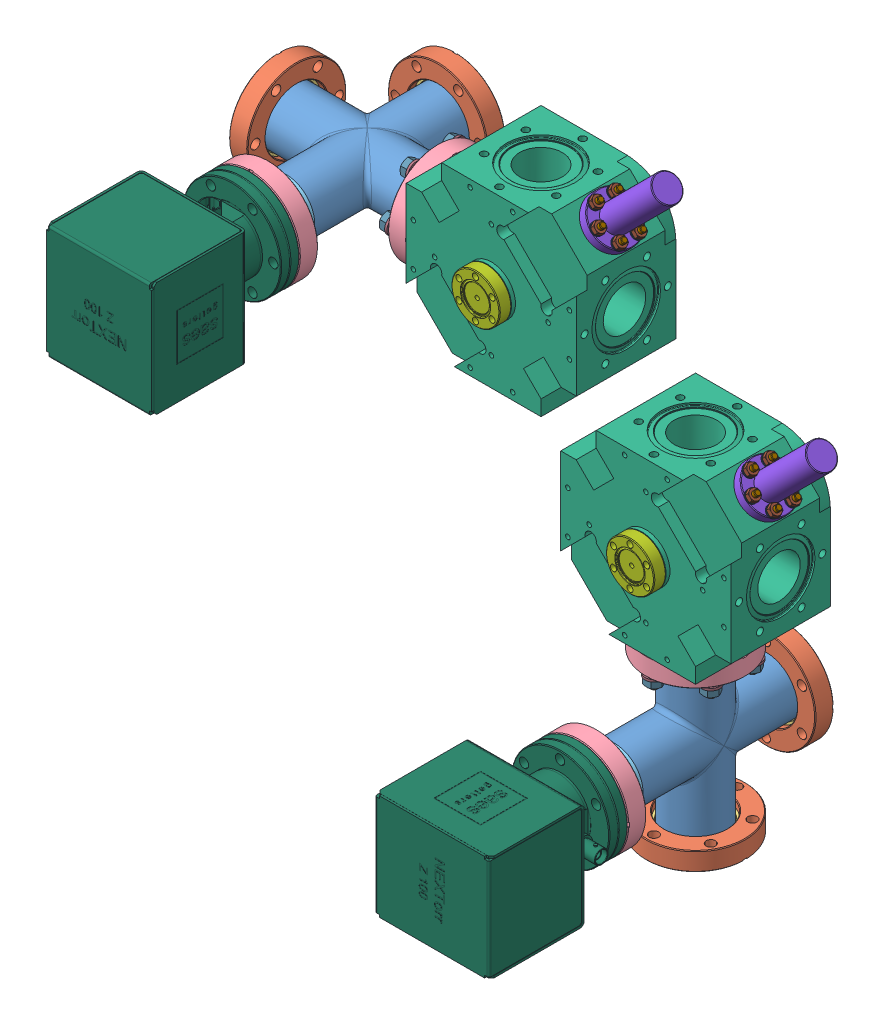
SolidWorks assembly 2D_MOT, configuration Standard. Lengths in mm.
Overall size (399.39 399.39 251.5).
105 component instances, 15 part files, 0 mates.
Components (placement in the parent):
- 2D_MOT.stp-1: 2D_MOT.stp [Standard] at origin size (399.39 399.39 251.5)
  - 17436-5-00.stp-1: 17436-5-00.stp [Standard] at (-122.5 0 0) x (0 0 1) z (1 0 0) size (145 95.35 125)
    - 17054-1-16.stp-1: 17054-1-16.stp [Standard] at origin size (114 40.07 114)
      - CROCE_DN40x1_5.stp-1: CROCE_DN40x1_5.stp [Standard] at origin size (114 40.07 114)
    - 17197-4-05.stp-1: 17197-4-05.stp [Standard] at (-56 0 0) x (0 -0.5 -0.866025) z (-1 0 0) size (69.8 69.8 13)
      - CFr40 collare.stp-1: CFr40 collare.stp [Standard] at origin size (69.8 69.8 13)
      - 17197-4-06.stp-1: 17197-4-06.stp [Standard] at (0 0 2.425) size (48.2 48.2 7.02)
    - 17197-4-05.stp-2: 17197-4-05.stp [Standard] at (0 0 -56) x (-0.866025 0.5 0) z (0 0 -1) size (69.8 69.8 13)
      - CFr40 collare.stp-1: CFr40 collare.stp [Standard] at origin size (69.8 69.8 13)
      - 17197-4-06.stp-1: 17197-4-06.stp [Standard] at (0 0 2.425) size (48.2 48.2 7.02)
    - 17197-4-04.stp-1: 17197-4-04.stp [Standard] at (0 0 56) x (-0.866025 -0.5 0) z (0 0 1) size (69.8 69.8 13)
    - 17197-4-04.stp-2: 17197-4-04.stp [Standard] at (76 0 0) x (0 -0.5 0.866025) z (1 0 0) size (69.8 69.8 13)
    - 17054-1-26.stp-1: 17054-1-26.stp [Standard] at (57 0 0) size (20 40 40)
  - 17436-5-00.stp-2: 17436-5-00.stp [Standard] at (108.8944 -231.3944 0) x (0 0 1) z (0 1 0) size (145 95.35 125)
    - 17054-1-16.stp-1: 17054-1-16.stp [Standard] at origin size (114 40.07 114)
      - CROCE_DN40x1_5.stp-1: CROCE_DN40x1_5.stp [Standard] at origin size (114 40.07 114)
    - 17197-4-05.stp-1: 17197-4-05.stp [Standard] at (-56 0 0) x (0 -0.5 -0.866025) z (-1 0 0) size (69.8 69.8 13)
      - CFr40 collare.stp-1: CFr40 collare.stp [Standard] at origin size (69.8 69.8 13)
      - 17197-4-06.stp-1: 17197-4-06.stp [Standard] at (0 0 2.425) size (48.2 48.2 7.02)
    - 17197-4-05.stp-2: 17197-4-05.stp [Standard] at (0 0 -56) x (-0.866025 0.5 0) z (0 0 -1) size (69.8 69.8 13)
      - CFr40 collare.stp-1: CFr40 collare.stp [Standard] at origin size (69.8 69.8 13)
      - 17197-4-06.stp-1: 17197-4-06.stp [Standard] at (0 0 2.425) size (48.2 48.2 7.02)
    - 17197-4-04.stp-1: 17197-4-04.stp [Standard] at (0 0 56) x (-0.866025 -0.5 0) z (0 0 1) size (69.8 69.8 13)
    - 17197-4-04.stp-2: 17197-4-04.stp [Standard] at (76 0 0) x (0 -0.5 0.866025) z (1 0 0) size (69.8 69.8 13)
    - 17054-1-26.stp-1: 17054-1-26.stp [Standard] at (57 0 0) size (20 40 40)
  - 17436-2-00.stp-1: 17436-2-00.stp [Standard] at origin size (120 120 97.8)
  - 17436-3-00.stp-1: 17436-3-00.stp [Standard] at (0 0 42) x (1 0 0) z (0 0 -1) size (34 34 31.2)
  - 17436-4-00.stp-1: 17436-4-00.stp [Standard] at (50.0456 50.0456 0) x (0.353553 -0.353553 0.866025) z (-0.707107 -0.707107 0) size (34 34 58.8)
  - UNI 5909 - M4 x 14.stp-1: UNI 5909 - M4 x 14.stp [Standard] at (47.5 47.5 -13.5) x (0.707107 0.707107 0) z (0.380389 -0.380389 0.842976) size (20 4 4)
  - UNI 6592 - 4,3 x 8.stp-1: UNI 6592 - 4,3 x 8.stp [Standard] at (44.3241 60.8582 6.75) x (0.707107 0.707107 0) z (0.604496 -0.604496 0.518814) size (0.8 8 8)
  - UNI 6592 - 4,3 x 8.stp-2: UNI 6592 - 4,3 x 8.stp [Standard] at (44.3241 60.8582 -6.75) x (0.707107 0.707107 0) z (-0.015459 0.015459 0.999761) size (0.8 8 8)
  - UNI 6592 - 4,3 x 8.stp-3: UNI 6592 - 4,3 x 8.stp [Standard] at (52.5912 52.5912 -13.5) x (0.707107 0.707107 0) z (-0.619956 0.619956 0.480947) size (0.8 8 8)
  - UNI 6592 - 4,3 x 8.stp-4: UNI 6592 - 4,3 x 8.stp [Standard] at (60.8582 44.3241 -6.75) x (0.707107 0.707107 0) z (-0.604496 0.604496 -0.518814) size (0.8 8 8)
  - UNI 6592 - 4,3 x 8.stp-5: UNI 6592 - 4,3 x 8.stp [Standard] at (60.8582 44.3241 6.75) x (0.707107 0.707107 0) z (0.015459 -0.015459 -0.999761) size (0.8 8 8)
  - UNI 6592 - 4,3 x 8.stp-6: UNI 6592 - 4,3 x 8.stp [Standard] at (52.5912 52.5912 13.5) x (0.707107 0.707107 0) z (0.619956 -0.619956 -0.480947) size (0.8 8 8)
  - UNI 5588 - M4.stp-1: UNI 5588 - M4.stp [Standard] at (55.4196 55.4196 -13.5) x (-0.707107 -0.707107 0) z (0 0 1) size (3.2 8.08 7)
  - UNI 5909 - M4 x 14.stp-2: UNI 5909 - M4 x 14.stp [Standard] at (55.767 39.233 -6.75) x (0.707107 0.707107 0) z (0.380389 -0.380389 0.842976) size (20 4 4)
  - UNI 5909 - M4 x 14.stp-3: UNI 5909 - M4 x 14.stp [Standard] at (55.767 39.233 6.75) x (0.707107 0.707107 0) z (0.380389 -0.380389 0.842976) size (20 4 4)
  - UNI 5909 - M4 x 14.stp-4: UNI 5909 - M4 x 14.stp [Standard] at (39.233 55.767 6.75) x (0.707107 0.707107 0) z (-0.645994 0.645994 0.406673) size (20 4 4)
  - UNI 5909 - M4 x 14.stp-5: UNI 5909 - M4 x 14.stp [Standard] at (39.233 55.767 -6.75) x (0.707107 0.707107 0) z (0.380389 -0.380389 0.842976) size (20 4 4)
  - UNI 5909 - M4 x 14.stp-6: UNI 5909 - M4 x 14.stp [Standard] at (47.5 47.5 13.5) x (0.707107 0.707107 0) z (-0.645994 0.645994 0.406673) size (20 4 4)
  - UNI 5588 - M4.stp-2: UNI 5588 - M4.stp [Standard] at (61.4239 44.8898 -6.75) x (0.707107 0.707107 0) z (0 0 -1) size (3.2 8.08 7)
  - UNI 5588 - M4.stp-3: UNI 5588 - M4.stp [Standard] at (61.4239 44.8898 6.75) x (0.707107 0.707107 0) z (0 0 -1) size (3.2 8.08 7)
  - UNI 5588 - M4.stp-4: UNI 5588 - M4.stp [Standard] at (53.1569 53.1569 13.5) x (0.707107 0.707107 0) z (0 0 -1) size (3.2 8.08 7)
  - UNI 5588 - M4.stp-5: UNI 5588 - M4.stp [Standard] at (44.8898 61.4239 6.75) x (0.707107 0.707107 0) z (0 0 -1) size (3.2 8.08 7)
  - UNI 5588 - M4.stp-6: UNI 5588 - M4.stp [Standard] at (44.8898 61.4239 -6.75) x (0.707107 0.707107 0) z (0 0 -1) size (3.2 8.08 7)
  - UNI 5909 - M6 x 20.stp-1: UNI 5909 - M6 x 20.stp [Standard] at (-61 0 -29.35) x (-1 0 0) z (0 0.537951 0.842976) size (29 6 6)
  - UNI 6592 - 6,4 x 12,5.stp-1: UNI 6592 - 6,4 x 12,5.stp [Standard] at (-73 0 -29.35) x (-1 0 0) z (0 0 1) size (1.6 12.5 12.5)
  - UNI 6592 - 6,4 x 12,5.stp-2: UNI 6592 - 6,4 x 12,5.stp [Standard] at (-73 -25.4178 -14.675) x (-1 0 0) z (0 0 1) size (1.6 12.5 12.5)
  - UNI 6592 - 6,4 x 12,5.stp-3: UNI 6592 - 6,4 x 12,5.stp [Standard] at (-73 25.4178 -14.675) x (-1 0 0) z (0 0 1) size (1.6 12.5 12.5)
  - UNI 6592 - 6,4 x 12,5.stp-4: UNI 6592 - 6,4 x 12,5.stp [Standard] at (-73 25.4178 14.675) x (-1 0 0) z (0 0 1) size (1.6 12.5 12.5)
  - UNI 6592 - 6,4 x 12,5.stp-5: UNI 6592 - 6,4 x 12,5.stp [Standard] at (-73 -25.4178 14.675) x (-1 0 0) z (0 0 1) size (1.6 12.5 12.5)
  - UNI 6592 - 6,4 x 12,5.stp-6: UNI 6592 - 6,4 x 12,5.stp [Standard] at (-73 0 29.35) x (-1 0 0) z (0 0 1) size (1.6 12.5 12.5)
  - UNI 5588 - M6.stp-1: UNI 5588 - M6.stp [Standard] at (-79.6 0 -29.35) size (5 11.55 10)
  - UNI 5588 - M6.stp-2: UNI 5588 - M6.stp [Standard] at (-79.6 -25.4178 14.675) size (5 11.55 10)
  - UNI 5588 - M6.stp-3: UNI 5588 - M6.stp [Standard] at (-79.6 25.4178 14.675) size (5 11.55 10)
  - UNI 5588 - M6.stp-4: UNI 5588 - M6.stp [Standard] at (-79.6 25.4178 -14.675) size (5 11.55 10)
  - UNI 5588 - M6.stp-5: UNI 5588 - M6.stp [Standard] at (-79.6 -25.4178 -14.675) size (5 11.55 10)
  - UNI 5588 - M6.stp-6: UNI 5588 - M6.stp [Standard] at (-79.6 0 29.35) size (5 11.55 10)
  - UNI 5909 - M6 x 20.stp-2: UNI 5909 - M6 x 20.stp [Standard] at (-61 25.4178 -14.675) x (-1 0 0) z (0 0.537951 0.842976) size (29 6 6)
  - UNI 5909 - M6 x 20.stp-3: UNI 5909 - M6 x 20.stp [Standard] at (-61 25.4178 14.675) x (-1 0 0) z (0 0.537951 0.842976) size (29 6 6)
  - UNI 5909 - M6 x 20.stp-4: UNI 5909 - M6 x 20.stp [Standard] at (-61 -25.4178 -14.675) x (-1 0 0) z (0 0.998204 0.059899) size (29 6 6)
  - UNI 5909 - M6 x 20.stp-5: UNI 5909 - M6 x 20.stp [Standard] at (-61 -25.4178 14.675) x (-1 0 0) z (0 0.537951 0.842976) size (29 6 6)
  - UNI 5909 - M6 x 20.stp-6: UNI 5909 - M6 x 20.stp [Standard] at (-61 0 29.35) x (-1 0 0) z (0 0.537951 0.842976) size (29 6 6)
  - 17436-2-00.stp-2: 17436-2-00.stp [Standard] at (108.8944 -108.8944 0) size (120 120 97.8)
  - 17436-3-00.stp-2: 17436-3-00.stp [Standard] at (108.8944 -108.8944 42) x (1 0 0) z (0 0 -1) size (34 34 31.2)
  - 5H0211 NT Z 100 rev0.1.stp-1: 5H0211 NT Z 100 rev0.1.stp [Standard] at (-122.5 0 83.2) x (0 1 0) z (0 0 -1) size (81.82 74.43 169.89)
  - UNI 6592 - 6,4 x 12,5.stp-7: UNI 6592 - 6,4 x 12,5.stp [Standard] at (108.8944 -181.8944 -29.35) x (0 -1 0) z (-0.010338 0 0.999947) size (1.6 12.5 12.5)
  - UNI 6592 - 6,4 x 12,5.stp-8: UNI 6592 - 6,4 x 12,5.stp [Standard] at (134.3123 -181.8944 -14.675) x (0 -1 0) z (0.007008 0 0.999975) size (1.6 12.5 12.5)
  - UNI 6592 - 6,4 x 12,5.stp-9: UNI 6592 - 6,4 x 12,5.stp [Standard] at (83.4766 -181.8944 -14.675) x (0 -1 0) z (0.006109 0 0.999981) size (1.6 12.5 12.5)
  - UNI 6592 - 6,4 x 12,5.stp-10: UNI 6592 - 6,4 x 12,5.stp [Standard] at (83.4766 -181.8944 14.675) x (0 -1 0) z (-0.00398 0 0.999992) size (1.6 12.5 12.5)
  - UNI 6592 - 6,4 x 12,5.stp-11: UNI 6592 - 6,4 x 12,5.stp [Standard] at (134.3123 -181.8944 14.675) x (0 -1 0) z (-0.008981 0 0.99996) size (1.6 12.5 12.5)
  - UNI 6592 - 6,4 x 12,5.stp-12: UNI 6592 - 6,4 x 12,5.stp [Standard] at (108.8944 -181.8944 29.35) x (0 -1 0) z (-0.007231 0 0.999974) size (1.6 12.5 12.5)
  - UNI 5588 - M6.stp-7: UNI 5588 - M6.stp [Standard] at (108.8944 -188.4944 -29.35) x (0 1 0) z (-0.0266 0 0.999646) size (5 11.55 10)
  - UNI 5588 - M6.stp-8: UNI 5588 - M6.stp [Standard] at (134.3123 -188.4944 14.675) x (0 1 0) z (-0.01581 0 0.999875) size (5 11.55 10)
  - UNI 5588 - M6.stp-9: UNI 5588 - M6.stp [Standard] at (83.4766 -188.4944 14.675) x (0 1 0) z (0.013805 0 0.999905) size (5 11.55 10)
  - UNI 5588 - M6.stp-10: UNI 5588 - M6.stp [Standard] at (83.4766 -188.4944 -14.675) x (0 1 0) z (0.032011 0 0.999488) size (5 11.55 10)
  - UNI 5588 - M6.stp-11: UNI 5588 - M6.stp [Standard] at (134.3123 -188.4944 -14.675) x (0 1 0) z (0 0 1) size (5 11.55 10)
  - UNI 5588 - M6.stp-12: UNI 5588 - M6.stp [Standard] at (108.8944 -188.4944 29.35) x (0 1 0) z (-0.005863 0 0.999983) size (5 11.55 10)
  - UNI 5909 - M6 x 20.stp-7: UNI 5909 - M6 x 20.stp [Standard] at (108.8944 -170.8944 -29.35) x (0 -1 0) z (-0.309921 0 -0.950762) size (29 6 6)
  - UNI 5909 - M6 x 20.stp-8: UNI 5909 - M6 x 20.stp [Standard] at (83.4766 -170.8944 -14.675) x (0 -1 0) z (0.983389 0 0.181512) size (29 6 6)
  - UNI 5909 - M6 x 20.stp-9: UNI 5909 - M6 x 20.stp [Standard] at (108.8944 -170.8944 29.35) x (0 -1 0) z (-0.999147 0 -0.041293) size (29 6 6)
  - UNI 5909 - M6 x 20.stp-10: UNI 5909 - M6 x 20.stp [Standard] at (83.4766 -170.8944 14.675) x (0 -1 0) z (-0.9977 0 0.06779) size (29 6 6)
  - UNI 5909 - M6 x 20.stp-11: UNI 5909 - M6 x 20.stp [Standard] at (134.3123 -170.8944 14.675) x (0 -1 0) z (-0.531269 0 0.847203) size (29 6 6)
  - UNI 5909 - M6 x 20.stp-12: UNI 5909 - M6 x 20.stp [Standard] at (134.3123 -170.8944 -14.675) x (0 -1 0) z (-0.967733 0 -0.251979) size (29 6 6)
  - 5H0211 NT Z 100 rev0.1.stp-2: 5H0211 NT Z 100 rev0.1.stp [Standard] at (108.8944 -231.3944 83.2) x (-1 0 0) z (0 0 -1) size (81.82 74.43 169.89)
  - 17436-4-00.stp-2: 17436-4-00.stp [Standard] at (158.94 -58.8489 0) x (0.353553 -0.353553 0.866025) z (-0.707107 -0.707107 0) size (34 34 58.8)
  - UNI 5909 - M4 x 14.stp-7: UNI 5909 - M4 x 14.stp [Standard] at (148.1274 -53.1274 6.75) x (0.707107 0.707107 0) z (0.380389 -0.380389 0.842976) size (20 4 4)
  - UNI 5909 - M4 x 14.stp-8: UNI 5909 - M4 x 14.stp [Standard] at (148.1274 -53.1274 -6.75) x (0.707107 0.707107 0) z (0.380389 -0.380389 0.842976) size (20 4 4)
  - UNI 5909 - M4 x 14.stp-9: UNI 5909 - M4 x 14.stp [Standard] at (156.3944 -61.3944 -13.5) x (0.707107 0.707107 0) z (0.380389 -0.380389 0.842976) size (20 4 4)
  - UNI 5909 - M4 x 14.stp-10: UNI 5909 - M4 x 14.stp [Standard] at (164.6615 -69.6615 6.75) x (0.707107 0.707107 0) z (0.380389 -0.380389 0.842976) size (20 4 4)
  - UNI 5909 - M4 x 14.stp-11: UNI 5909 - M4 x 14.stp [Standard] at (164.6615 -69.6615 -6.75) x (0.707107 0.707107 0) z (0.380389 -0.380389 0.842976) size (20 4 4)
  - UNI 5909 - M4 x 14.stp-12: UNI 5909 - M4 x 14.stp [Standard] at (156.3944 -61.3944 13.5) x (0.707107 0.707107 0) z (0.380389 -0.380389 0.842976) size (20 4 4)
  - UNI 6592 - 4,3 x 8.stp-7: UNI 6592 - 4,3 x 8.stp [Standard] at (161.4856 -56.3033 -13.5) x (0.707107 0.707107 0) z (0 0 1) size (0.8 8 8)
  - UNI 6592 - 4,3 x 8.stp-8: UNI 6592 - 4,3 x 8.stp [Standard] at (161.4856 -56.3033 13.5) x (0.707107 0.707107 0) z (0 0 1) size (0.8 8 8)
  - UNI 6592 - 4,3 x 8.stp-9: UNI 6592 - 4,3 x 8.stp [Standard] at (169.7526 -64.5703 6.75) x (0.707107 0.707107 0) z (0 0 1) size (0.8 8 8)
  - UNI 6592 - 4,3 x 8.stp-10: UNI 6592 - 4,3 x 8.stp [Standard] at (169.7526 -64.5703 -6.75) x (0.707107 0.707107 0) z (0 0 1) size (0.8 8 8)
  - UNI 6592 - 4,3 x 8.stp-11: UNI 6592 - 4,3 x 8.stp [Standard] at (153.2186 -48.0362 -6.75) x (0.707107 0.707107 0) z (0 0 1) size (0.8 8 8)
  - UNI 6592 - 4,3 x 8.stp-12: UNI 6592 - 4,3 x 8.stp [Standard] at (153.2186 -48.0362 6.75) x (0.707107 0.707107 0) z (0 0 1) size (0.8 8 8)
  - UNI 5588 - M4.stp-7: UNI 5588 - M4.stp [Standard] at (172.5811 -61.7419 -6.75) x (-0.707107 -0.707107 0) z (0 0 1) size (3.2 8.08 7)
  - UNI 5588 - M4.stp-8: UNI 5588 - M4.stp [Standard] at (172.5811 -61.7419 6.75) x (-0.707107 -0.707107 0) z (0 0 1) size (3.2 8.08 7)
  - UNI 5588 - M4.stp-9: UNI 5588 - M4.stp [Standard] at (164.314 -53.4748 -13.5) x (-0.707107 -0.707107 0) z (0 0 1) size (3.2 8.08 7)
  - UNI 5588 - M4.stp-10: UNI 5588 - M4.stp [Standard] at (156.047 -45.2078 -6.75) x (-0.707107 -0.707107 0) z (0 0 1) size (3.2 8.08 7)
  - UNI 5588 - M4.stp-11: UNI 5588 - M4.stp [Standard] at (156.047 -45.2078 6.75) x (-0.707107 -0.707107 0) z (0 0 1) size (3.2 8.08 7)
  - UNI 5588 - M4.stp-12: UNI 5588 - M4.stp [Standard] at (164.314 -53.4748 13.5) x (-0.707107 -0.707107 0) z (0 0 1) size (3.2 8.08 7)
